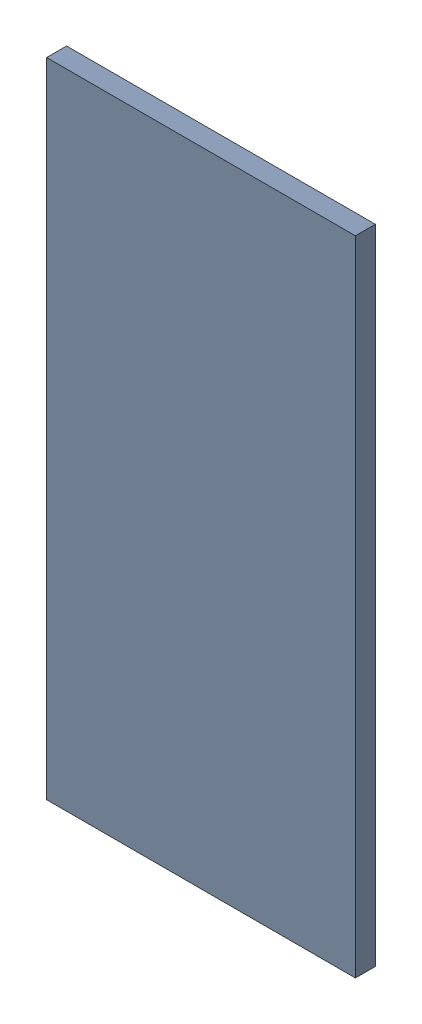
SolidWorks assembly Pad ADXL345-6(19mm,58.097mm) on Top Layer, configuration Predeterminado. Lengths in mm.
Overall size (0.55 1.15 0.04).
2 component instances, 1 part files, 0 mates.
Components (placement in the parent):
- Pad ADXL345-6(19mm,58.097mm) on Top Layer-1-1: Pad ADXL345-6(19mm,58.097mm) on Top Layer-1 [Predeterminado] at (-68.317 -44.187 -0.0457) size (0.55 1.15 0.04)
  - Pad ADXL345-6(19mm,58.097mm) on Top Layer-Part-1-1: Pad ADXL345-6(19mm,58.097mm) on Top Layer-Part-1 [Predeterminado] at origin size (0.55 1.15 0.04)
